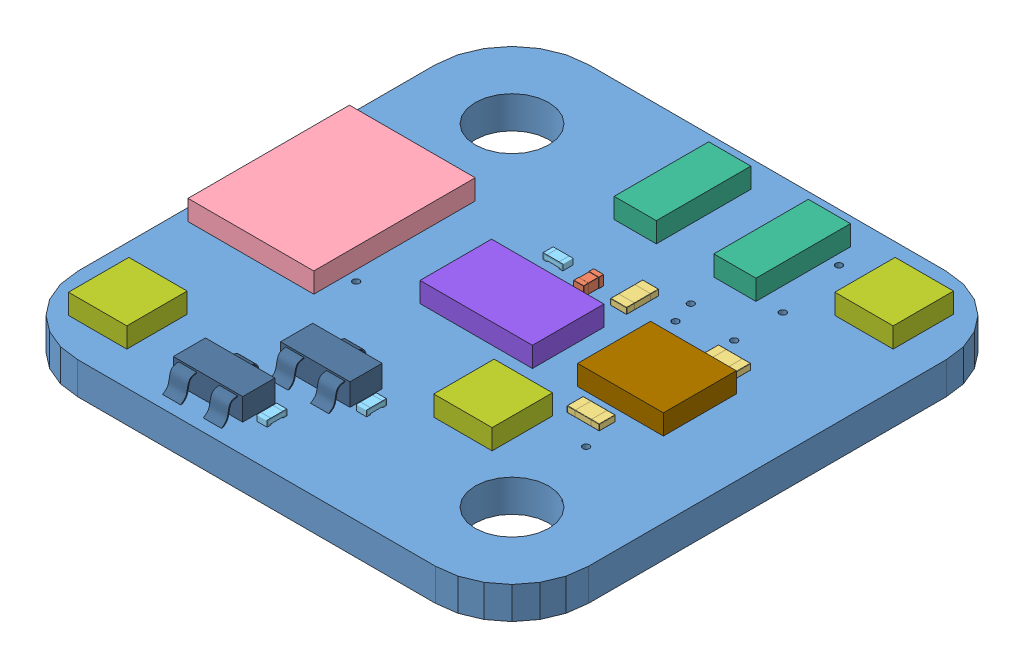
SolidWorks assembly smartstandheadphonedetectionrevc, configuration Default. Lengths in mm.
Overall size (25.4 2.7 25.4).
20 component instances, 10 part files, 0 mates.
Components (placement in the parent):
- smartstandheadphonedetectionrevc-1: smartstandheadphonedetectionrevc [Default] at origin size (25.4 1.6 25.4)
- C0402-1: C0402 [Default] at (13.462 1.6 -15.748) x (0 0 -1) z (0 1 0) size (1 0.5 0.5)
- C0603-1: C0603 [Default] at (20.193 1.6 -15.875) x (-1 0 0) z (0 1 0) size (1.6 0.8 0.3)
- C0603-2: C0603 [Default] at (19.05 1.6 -10.287) x (1 0 0) z (0 1 0) size (1.6 0.8 0.3)
- C0603-3: C0603 [Default] at (15.113 1.6 -16.383) x (0 0 -1) z (0 1 0) size (1.6 0.8 0.3)
- T1MSINGLE5POS_T1M5POS-1: T1MSINGLE5POS_T1M5POS [Default] at (3.048 1.6 -12.7) x (0 0 -1) z (0 1 0) size (8.03 6.25 1)
- R0402-1: R0402 [Default] at (11.557 1.6 -16.129) x (1 0 0) z (0 1 0) size (1.01 0.5 0.32)
- R0402-2: R0402 [Default] at (11.176 1.6 -2.286) x (0 0 1) z (0 1 0) size (1.01 0.5 0.32)
- R0402-3: R0402 [Default] at (13.208 1.6 -5.207) x (0 0 1) z (0 1 0) size (1.01 0.5 0.32)
- R0402-4: R0402 [Default] at (8.763 1.6 -6.096) x (0 0 -1) z (0 1 0) size (1.01 0.5 0.32)
- R0402-5: R0402 [Default] at (6.731 1.6 -3.048) x (0 0 -1) z (0 1 0) size (1.01 0.5 0.32)
- TESTPOINT1_5WITHGND_TESTPOINTWITHGND-1: TESTPOINT1_5WITHGND_TESTPOINTWITHGND [Default] at (12.192 1.6 -21.717) x (0 0 -1) z (0 1 0) size (4.7 2.1 1)
- TESTPOINT1_5WITHGND_TESTPOINTWITHGND-2: TESTPOINT1_5WITHGND_TESTPOINTWITHGND [Default] at (17.145 1.6 -21.717) x (0 0 -1) z (0 1 0) size (4.7 2.1 1)
- FIDUCIAL_1MM_FIDUCIAL1MM-1: FIDUCIAL_1MM_FIDUCIAL1MM [Default] at (22.225 1.6 -22.225) size (2.9 1 3)
- FIDUCIAL_1MM_FIDUCIAL1MM-2: FIDUCIAL_1MM_FIDUCIAL1MM [Default] at (3.175 1.6 -3.175) size (2.9 1 3)
- FIDUCIAL_1MM_FIDUCIAL1MM-3: FIDUCIAL_1MM_FIDUCIAL1MM [Default] at (16.637 1.6 -7.874) size (2.9 1 3)
- VL6180X_VL6180XV0NR-1: VL6180X_VL6180XV0NR [Default] at (12.7 1.6 -12.7) size (5.59 1 3.56)
- RPDSOG5DBV_LP5907MFX2_8-1: RPDSOG5DBV_LP5907MFX2_8 [Default] at (19.558 1.6 -13.081) x (0 0 -1) z (1 0 0) size (3.63 1 4.26)
- sot23_4210037-1: sot23_4210037 [Default] at (10.922 1.6 -5.588) x (0 0 -1) z (0 1 0) size (3.22 3.45 1.11)
- sot23_4210037-2: sot23_4210037 [Default] at (8.89 1.6 -2.286) x (0 0 -1) z (0 1 0) size (3.22 3.45 1.11)
